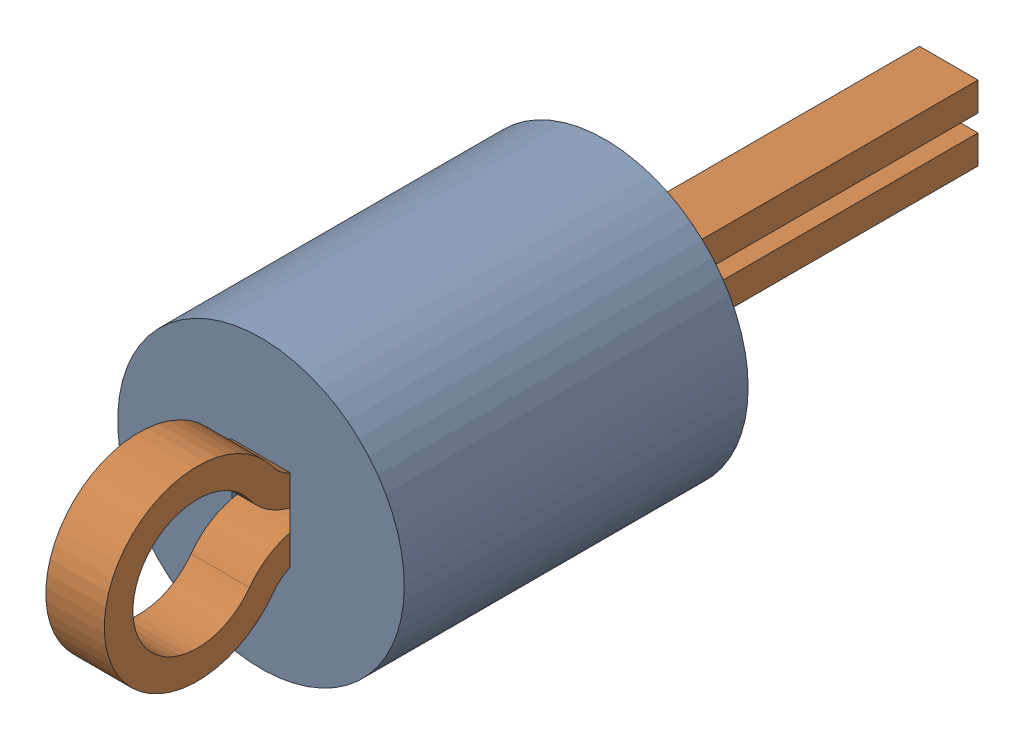
SolidWorks assembly TP4, configuration Default. Lengths in mm.
Overall size (2.5 2.5 7.62).
3 component instances, 2 part files, 0 mates.
Components (placement in the parent):
- Keystone_5002-1: Keystone_5002 [Default] at (37.5875 48.7709 0) size (2.5 2.5 7.62)
  - Keystone5002_white-1: Keystone5002_white [Default] at origin size (2.5 2.5 3)
  - Keystone500x_wire-1: Keystone500x_wire [Default] at origin size (0.51 1.62 7.62)
